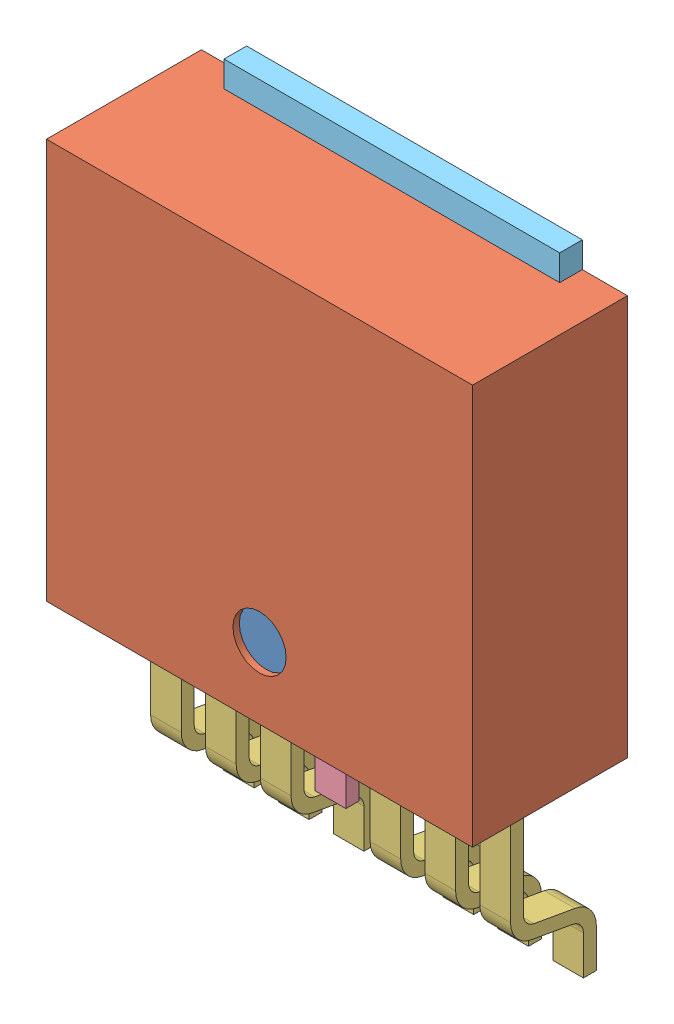
SolidWorks assembly VN50, configuration Default. Lengths in mm.
Overall size (7.01 9.73 2.43).
13 component instances, 5 part files, 0 mates.
Components (placement in the parent):
- U_-1: U_ [Default] at origin size (7.01 9.73 2.43)
  - 464982512-1: 464982512 [Default] at (13.2334 62.038 0) x (0 1 0) z (0 0 1) size (9.73 7.01 2.43)
    - Open_CASCADE_STEP_translator_6.8_5.1-1: Open_CASCADE_STEP_translator_6.8_5.1 [Default] at (-3.1 -3.3 0) size (0.83 0.83 0)
    - Body-1: Body [Default] at (-3.1 -3.3 0) size (6.2 6.6 2.4)
      - Open_CASCADE_STEP_translator_6.8_5.2.1-1: Open_CASCADE_STEP_translator_6.8_5.2.1 [Default] at origin size (6.2 6.6 2.4)
    - Lead-1: Lead [Default] at (-3.1 -2.55 0) x (-1 0 0) z (0 0 1) size (3.13 0.48 1.33)
    - Lead-2: Lead [Default] at (-3.1 -1.7 0) x (-1 0 0) z (0 0 1) size (3.13 0.48 1.33)
    - Lead-3: Lead [Default] at (-3.1 -0.85 0) x (-1 0 0) z (0 0 1) size (3.13 0.48 1.33)
    - Trimmed_Lead-1: Trimmed_Lead [Default] at (-3.1 -0.2375 1.13) size (1.56 0.47 0.2)
    - Lead-4: Lead [Default] at (-3.1 0.85 0) x (-1 0 0) z (0 0 1) size (3.13 0.48 1.33)
    - Lead-5: Lead [Default] at (-3.1 1.7 0) x (-1 0 0) z (0 0 1) size (3.13 0.48 1.33)
    - Lead-6: Lead [Default] at (-3.1 2.55 0) x (-1 0 0) z (0 0 1) size (3.13 0.48 1.33)
    - tab-1: tab [Default] at (-3.1 -3.3 0) size (5.1 5.2 0.35)
